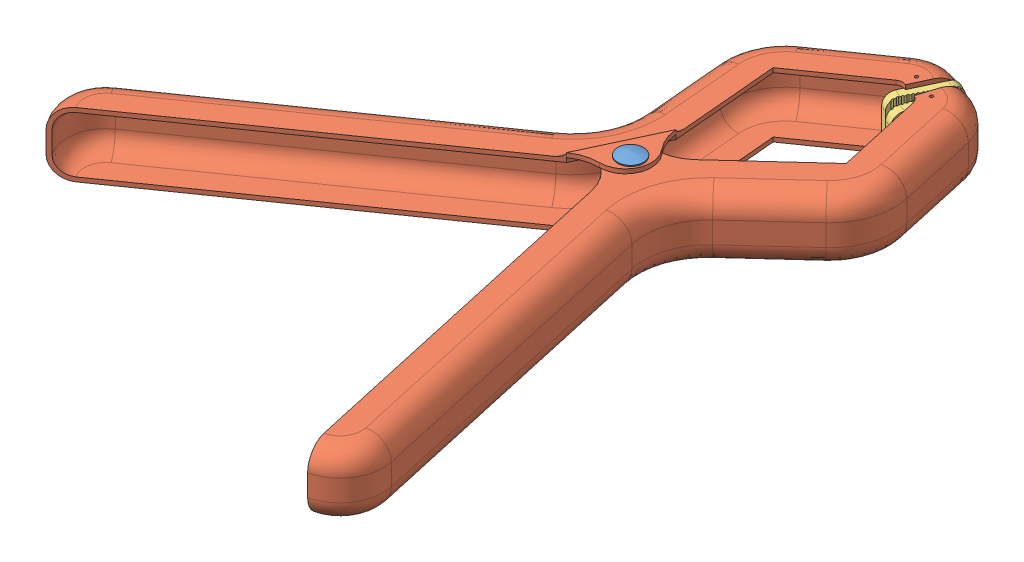
SolidWorks assembly Assem2, configuration Default. Lengths in mm.
Overall size (152.82 19.96 174.12).
5 component instances, 3 part files, 11 mates.
Components (placement in the parent):
- pinnetje van de lijmklem-1: pinnetje van de lijmklem [Default] at (-26.8597 -6.1269 10.3963) size (6 19.96 6)
- lijmklem handvat-1: lijmklem handvat [Default] at (-1.8336 -3.1269 -45.3169) x (0 1 0) z (0.300965 0 -0.953635) size (15.58 56.61 145.3)
- lijmklem handvat-2: lijmklem handvat [lijmklem handvat met toevoeging<As Machined>] at (-3.8188 11.8731 -46.0895) x (0 -1 0) z (0.422865 0 -0.906193) size (17 56.61 145.3)
- knijper blokje-1: knijper blokje [Default] at (-6.8136 -2.1269 -31.1609) x (0.334063 0 -0.942551) z (0.942551 0 0.334063) size (14 14.3 6.52)
- knijper blokje-2: knijper blokje [Default] at (-2.037 -1.9269 -45.1811) x (-0.454233 0 0.890883) z (-0.890883 0 -0.454233) size (14 14.3 6.52)
Mates (geometry in assembly coordinates):
- Concentric1: concentric: cylinder of pinnetje van de lijmklem-1 through (-24.6597 13.8287 10.3963) axis (0 1 0) radius 2.2; cylinder of lijmklem handvat-2 through (-24.6597 -3.1269 10.3963) axis (0 1 0) radius 2
- Concentric3: concentric: cylinder of pinnetje van de lijmklem-1 through (-24.6597 13.8287 10.3963) axis (0 1 0) radius 2.2; cylinder of lijmklem handvat-1 through (-24.6597 11.8731 10.3963) axis (0 -1 0) radius 2
- Coincident2: coincident: plane of lijmklem handvat-1 through (-3.7578 11.8731 -35.5038) normal (0 1 0); plane of lijmklem handvat-2 through (-42.6068 11.8731 57.1974) normal (0 -1 0)
- Coincident3: coincident: plane of pinnetje van de lijmklem-1 through (-26.8597 12.8731 10.3963) normal (0 -1 0); plane of lijmklem handvat-2 through (-27.0891 12.8731 25.3495) normal (0 1 0)
- Coincident5: coincident: plane of lijmklem handvat-2 through (-9.0344 10.8731 -37.5574) normal (0 -1 0); plane of knijper blokje-2 through (-3.8188 10.8731 -46.0895) normal (0 1 0)
- Coincident6: coincident: line of lijmklem handvat-2 through (-3.8188 1.8731 -46.0895) axis (0 1 0); line of knijper blokje-2 through (-3.8188 8.3731 -46.0895) axis (0 -1 0)
- Parallel2: parallel: plane of lijmklem handvat-2 through (-3.8188 -3.1269 -46.0895) normal (0.906193 0 0.422865); plane of knijper blokje-2 through (-4.291 10.8731 -46.2329) normal (-0.906193 0 -0.422865)
- Coincident8: coincident: plane of lijmklem handvat-1 through (-3.7578 -2.1269 -35.5038) normal (0 1 0); plane of knijper blokje-1 through (-4.9285 -2.1269 -30.4928) normal (0 -1 0)
- Coincident9: coincident: line of lijmklem handvat-1 through (-2.1367 6.8731 -44.3566) axis (0 -1 0); line of knijper blokje-1 through (-2.1367 0.3731 -44.3566) axis (0 1 0)
- Parallel3: parallel: line of lijmklem handvat-1 through (-3.3577 10.8731 -40.4878) axis (-0.300965 0 0.953635); line of knijper blokje-1 through (-1.0045 10.6731 -41.3029) axis (-0.300965 0 0.953635)
- Angle2: planar angle = 1.963495 rad: plane of lijmklem handvat-2 through (-32.8226 -3.1269 17.1564) normal (0.573354 0 0.819308); plane of lijmklem handvat-1 through (-23.2141 11.8731 20.896) normal (-0.976355 0 0.216174)
